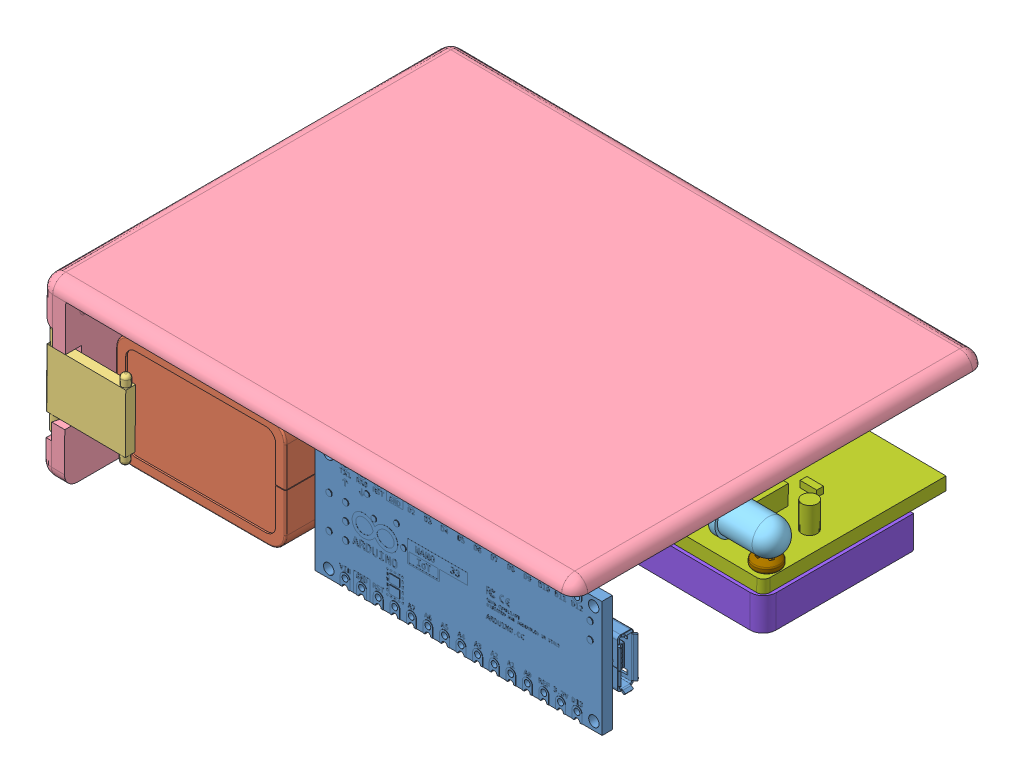
SolidWorks assembly ECG Assembly, configuration Default. Lengths in mm.
Overall size (82.99 27.71 63.25).
13 component instances, 10 part files, 19 mates.
Components (placement in the parent):
- Arduino Nano 33 IoT-1: Arduino Nano 33 IoT [Default] at (62.6902 45.5162 92.7098) x (0.002238 -0.999997 0) z (0.999997 0.002238 0) size (17.78 5.55 45.32)
- 9V-battery-1: 9V-battery [Default] at (42.7078 52.8996 3.7502) x (1 0 0) z (0 -1 0) size (26.04 47.88 17.14)
- Box Locking Part-1: Box Locking Part [Default] at (17.4382 51.7582 37.7598) x (-0.999962 0.008727 0) z (0.008727 0.999962 0) size (12.2 1.5 14)
- Box Locking Part-2: Box Locking Part [Default] at (17.3596 42.7585 99.2599) x (-0.999962 0.008727 -0.000038) z (-0.008727 -0.999962 0) size (12.2 1.5 14)
- ECG box-1: ECG box [Default] at (6.754 59.3517 37.0098) x (0.999962 -0.008727 0) z (0 0 -1)
- ECG Box Lid-1: ECG Box Lid [Default] at (4.7395 59.3693 99.7598) x (0.008727 0.999962 0) z (0 0 -1) size (27 82 63)
- Led RGB 5mm-1: Led RGB 5mm [Valor predeterminado] at (73.6827 50.8808 68.3093) x (0.003093 0.354454 0.935068) z (0.00816 0.935033 -0.354467) size (5.6 15.8 5.8)
  - Lente^Led RGB 5mm-1: Lente^Led RGB 5mm [Valor predeterminado] at origin size (5.6 8.8 5.8) (virtual)
  - Terminais^Led RGB 5mm-1: Terminais^Led RGB 5mm [Valor predeterminado] at origin size (4.82 11.92 1.55) (virtual)
- ECG module-1: ECG module [Default] at (82.5941 40.6892 66.7098) x (0 0 -1) z (0.999962 -0.008727 0) size (28 10 35)
- Spacer Short-1: Spacer Short [Default] at (47.0518 35.9991 38.2098) x (0 0 1) z (-0.999962 0.008727 0) size (23.04 5 36)
- Part37-1: Part37 [Default] at (80.6116 42.7065 64.2098) x (0.950765 -0.008297 0.309803) z (-0.309791 0.002704 0.950801) size (4 9.86 4)
- Part37-2: Part37 [Default] at (49.6128 42.9771 64.2098) x (0.192922 -0.001684 0.981213) z (-0.981175 0.008563 0.192929) size (4 9.86 4)
Mates (geometry in assembly coordinates):
- Coincident3: coincident: plane of ECG box-1 through (8.5533 36.3351 41.0098) normal (0 0 1); plane of ECG Box Lid-1 through (78.7367 58.7235 41.0098) normal (0 0 -1)
- Coincident4: coincident: plane of ECG box-1 through (6.754 59.3517 37.0098) normal (0.008727 0.999962 0); plane of ECG Box Lid-1 through (86.7364 58.6537 36.7598) normal (-0.008727 -0.999962 0)
- Concentric1: concentric: circle of Arduino Nano 33 IoT-1; circle of ECG box-1
- Distance1: distance = 2.5 mm: plane of Arduino Nano 33 IoT-1 through (62.6902 45.5162 93.5098) normal (0 0 1); plane of ECG box-1 through (8.5533 36.3351 96.0098) normal (0 0 -1)
- Concentric2: concentric: cylinder of Box Locking Part-1 through (16.5966 41.2651 38.5098) axis (0.008727 0.999962 0) radius 0.65; cylinder of ECG box-1 through (16.5922 40.7651 38.5098) axis (0.008727 0.999962 0) radius 0.875
- Distance2: distance = 0.5 mm: plane of Box Locking Part-1 through (17.4382 51.7582 39.2598) normal (0.008727 0.999962 0); plane of ECG box-1 through (8.6929 52.3345 39.5098) normal (-0.008727 -0.999962 0)
- Concentric3: concentric: cylinder of Box Locking Part-2 through (16.7013 53.2646 98.5098) axis (-0.008727 -0.999962 0) radius 0.65; cylinder of ECG box-1 through (16.5922 40.7651 98.5098) axis (0.008727 0.999962 0) radius 0.875
- Distance3: distance = 0.5 mm: plane of Box Locking Part-2 through (17.4382 51.7582 97.7599) normal (0.008727 0.999962 0); plane of ECG box-1 through (8.6929 52.3345 97.5098) normal (-0.008727 -0.999962 0)
- Distance4: distance = 0 mm: plane of Led RGB 5mm-1/Lente^Led RGB 5mm-1 through (79.6824 50.8285 68.3093) normal (0.999962 -0.008727 0); plane of ECG box-1 through (79.7513 58.7146 37.0098) normal (-0.999962 0.008727 0)
- Concentric4: concentric: cylinder of ECG box-1 through (49.4644 25.9777 64.2098) axis (0.008727 0.999962 0) radius 1.25; cylinder of ECG module-1 through (49.6128 42.9771 64.2098) axis (-0.008727 -0.999962 0) radius 1.5
- Concentric5: concentric anti-aligned: circle of ECG box-1; cylinder of ECG module-1 through (80.6116 42.7065 64.2098) axis (-0.008727 -0.999962 0) radius 1.5
- Concentric6: concentric anti-aligned: circle of ECG box-1; cylinder of Spacer Short-1 through (49.5953 40.9771 64.2098) axis (-0.008727 -0.999962 0) radius 1.5
- Concentric7: concentric: cylinder of ECG box-1 through (80.4632 25.7072 64.2098) axis (0.008727 0.999962 0) radius 1.25; cylinder of Spacer Short-1 through (80.5941 40.7066 64.2098) axis (-0.008727 -0.999962 0) radius 1.5
- Coincident6: coincident: plane of ECG box-1 through (6.5533 36.3526 37.0098) normal (0.008727 0.999962 0); plane of Spacer Short-1 through (47.0518 35.9991 38.2098) normal (-0.008727 -0.999962 0)
- Coincident7: coincident anti-aligned: plane of ECG module-1 through (82.5941 40.6892 66.7098) normal (-0.008727 -0.999962 0); plane of Spacer Short-1 through (47.0954 40.9989 38.2098) normal (0.008727 0.999962 0)
- Concentric8: concentric aligned: cylinder of ECG module-1 through (80.6116 42.7065 64.2098) axis (-0.008727 -0.999962 0) radius 1.5; cylinder of Part37-1 through (80.6272 44.4915 64.2098) axis (-0.008727 -0.999962 0) radius 2
- Coincident8: coincident anti-aligned: plane of ECG module-1 through (82.6115 42.6891 66.7098) normal (0.008727 0.999962 0); plane of Part37-1 through (80.6116 42.7065 64.2098) normal (-0.008727 -0.999962 0)
- Concentric9: concentric aligned: cylinder of ECG module-1 through (49.6128 42.9771 64.2098) axis (-0.008727 -0.999962 0) radius 1.5; cylinder of Part37-2 through (49.6284 44.762 64.2098) axis (-0.008727 -0.999962 0) radius 2
- Coincident9: coincident anti-aligned: plane of ECG module-1 through (82.6115 42.6891 66.7098) normal (0.008727 0.999962 0); plane of Part37-2 through (49.6128 42.9771 64.2098) normal (-0.008727 -0.999962 0)
